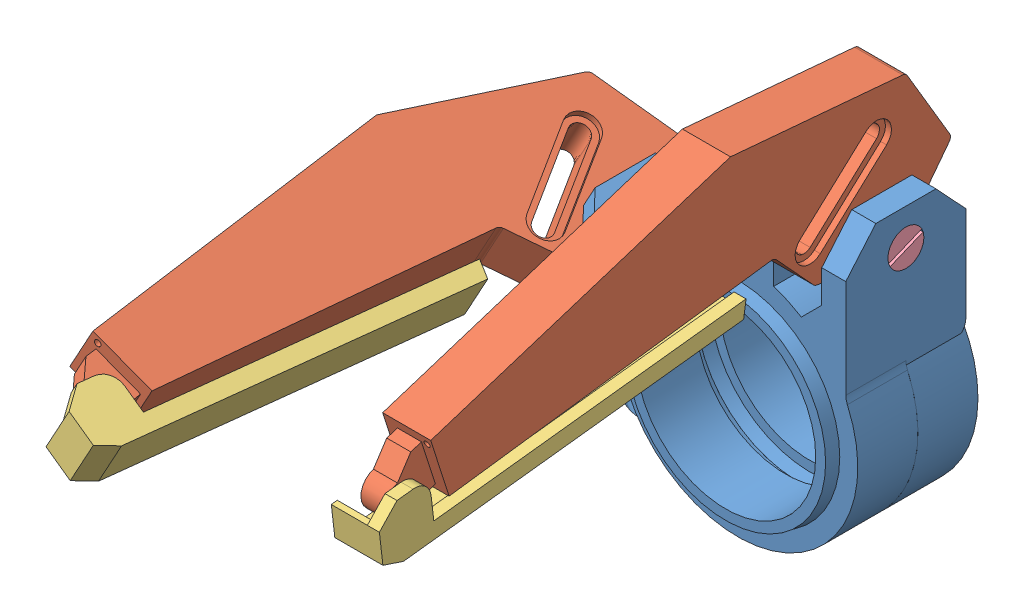
SolidWorks assembly Assem1, configuration Default. Lengths in mm.
Overall size (84.75 81.02 98.19).
8 component instances, 4 part files, 7 mates.
Components (placement in the parent):
- CrawPivotL-1: CrawPivotL [Default] at (21.534 26.9289 38.4604) size (40 51.64 22.18)
- CrawPivotL-2: CrawPivotL [Default] at (21.534 26.9289 38.4604) x (-0.480333 -0.877086 0) z (0 0 -1) size (40 51.64 22.18)
- FrontCraw-1: FrontCraw [Default] at (-19.1991 33.2743 114.7495) x (0.061509 -0.033685 -0.997538) z (0.874927 -0.47915 0.070129) size (92.48 8 30.71)
- FrontCraw-2: FrontCraw [Default] at (27.534 50.0637 115.8312) x (0 0.132288 -0.991211) z (0 -0.991211 -0.132288) size (92.48 8 30.71)
- UpperSecCraw-1: UpperSecCraw [Default] at (30.534 52.1159 116.1437) x (0 0.115132 -0.99335) z (1 0 0) size (60.97 9.37 8)
- UpperSecCraw-2: UpperSecCraw [Default] at (-19.5764 36.9013 114.6421) x (0.072807 -0.039872 -0.996549) z (0.480333 0.877086 0) size (60.97 9.37 8)
- M4-1: M4 [Default] at (39.534 52.5693 38.4604) x (0 -0.381849 0.924225) z (0 -0.924225 -0.381849) size (6 16 6)
- M4-2: M4 [Default] at (-9.6008 23.4572 38.4604) x (0.877086 -0.480333 0) z (0 0 1) size (6 16 6)
Mates (geometry in assembly coordinates):
- Coincident1: coincident anti-aligned: circle of CrawPivotL-1; circle of CrawPivotL-2
- Coincident2: coincident aligned: circle of CrawPivotL-2; circle of FrontCraw-1
- Coincident3: coincident anti-aligned: circle of CrawPivotL-1; circle of FrontCraw-2
- Coincident4: coincident aligned: circle of FrontCraw-2; circle of UpperSecCraw-1
- Coincident5: coincident aligned: circle of FrontCraw-1; circle of UpperSecCraw-2
- Coincident6: coincident aligned: circle of CrawPivotL-2; circle of M4-2
- Coincident7: coincident aligned: circle of CrawPivotL-1; circle of M4-1
